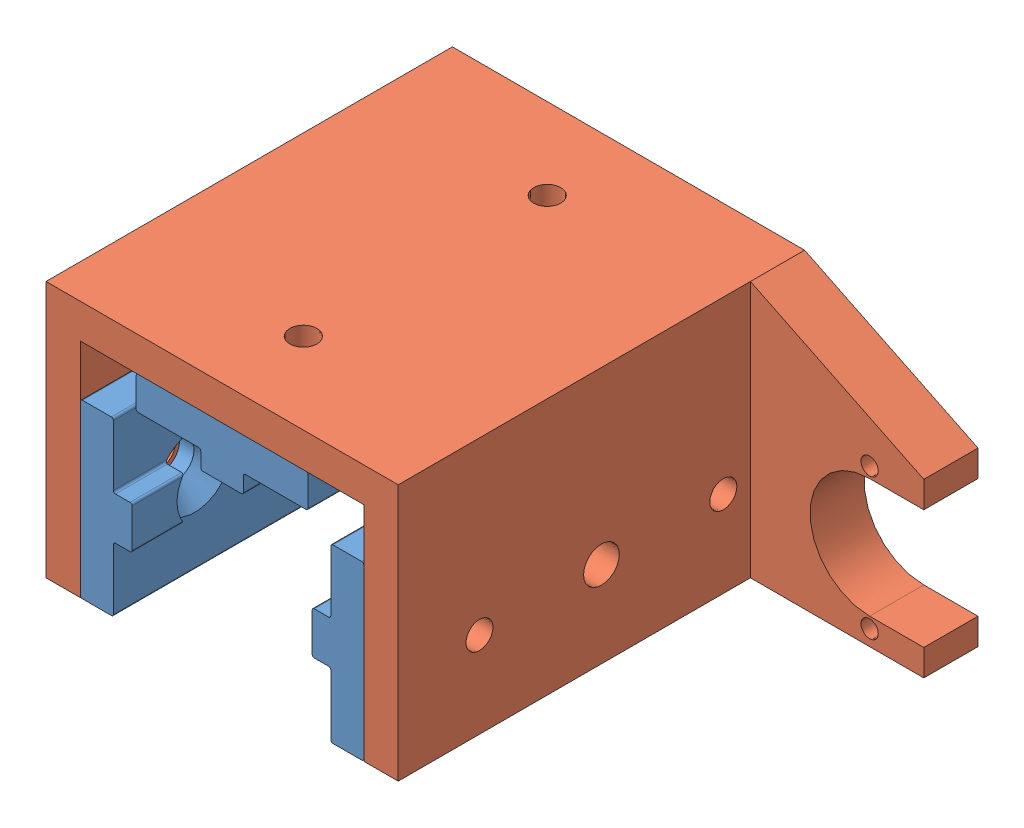
SolidWorks assembly Frame Carriage Assembly RH, configuration Default. Lengths in mm.
Overall size (97 47.37 75).
4 component instances, 2 part files, 19 mates.
Components (placement in the parent):
- Frame Carriage Bearing-1: Frame Carriage Bearing [Default] at (-8.5993 49.5816 28.728) size (9.53 31.75 75)
- Frame Carriage Bearing-2: Frame Carriage Bearing [Default] at (31.5087 49.5816 28.728) x (-1 0 0) z (0 0 1) size (9.53 31.75 75)
- Frame Carriage Bearing-3: Frame Carriage Bearing [Default] at (11.4547 68.6316 78.328) x (0 -1 0) z (0 0 -1) size (9.53 31.75 75)
- Frame Carriage Body RH-1: Frame Carriage Body RH [Default] at (-21.0453 33.7076 -58.972) size (97 47.37 75)
Mates (geometry in assembly coordinates):
- Coincident1: coincident: plane of ? through (-13.8584 24.4943 92.1884) normal (0 0 1); plane of Frame Carriage Bearing-1 through (-7.1274 55.8623 92.1884) normal (0 0 1)
- Coincident2: coincident: plane of ? through (-13.8584 24.4943 92.1884) normal (0 0 1); plane of Frame Carriage Bearing-3 through (34.1356 65.1333 92.1884) normal (0 0 1)
- Coincident3: coincident: plane of ? through (-13.8584 24.4943 92.1884) normal (0 0 1); plane of Frame Carriage Bearing-2 through (44.4106 24.8743 92.1884) normal (0 0 1)
- Coincident4: coincident: plane of ? through (-7.5084 24.4943 92.1884) normal (1 0 0); plane of Frame Carriage Bearing-1 through (-7.5084 55.8623 42.5884) normal (-1 0 0)
- Coincident5: coincident: plane of ? through (44.7916 65.5143 92.1884) normal (-1 0 0); plane of Frame Carriage Bearing-2 through (44.7916 24.8743 42.5884) normal (1 0 0)
- Coincident6: coincident: plane of ? through (-7.5084 65.5143 92.1884) normal (0 -1 0); plane of Frame Carriage Bearing-3 through (3.1476 65.5143 66.7884) normal (0 1 0)
- Distance2: distance = 19.05 mm: moEndPointRef_w of Frame Carriage Bearing-1; line of Frame Carriage Bearing-3 through (7.1367 68.6316 91.028) axis (-1 0 0)
- Coincident10: coincident: plane of Frame Carriage Bearing-1 through (-14.3143 33.7066 41.428) normal (0 -1 0); plane of Frame Carriage Bearing-2 through (31.8897 33.7066 41.428) normal (0 -1 0)
- Symmetric1: symmetric: plane of Frame Carriage Bearing-3 through (-4.4203 69.0126 65.628) normal (-1 0 0); plane of Frame Carriage Bearing-3 through (27.3297 74.3466 65.628) normal (1 0 0); plane of assembly
- Coincident11: coincident: plane of Frame Carriage Bearing-3 through (36.218 70.7626 91.1503) normal (0 0 1); plane of ? through (-11.776 30.1509 91.1503) normal (0 0 1)
- Coincident12: coincident: plane of Frame Carriage Bearing-2 through (46.874 30.5319 42.5884) normal (1 0 0); plane of ? through (46.874 71.1709 91.1503) normal (-1 0 0)
- Coincident13: coincident: plane of Frame Carriage Bearing-2 through (41.159 30.1509 42.5884) normal (0 -1 0); plane of ? through (53.224 30.1509 91.1503) normal (0 -1 0)
- Coincident14: coincident: plane of Frame Carriage Bearing-1 through (-5.426 61.5199 42.5884) normal (-1 0 0); plane of ? through (-5.426 30.1509 91.1503) normal (1 0 0)
- Coincident15: coincident: plane of Frame Carriage Bearing-1 through (-14.6953 65.0756 41.428) normal (-1 0 0); plane of Frame Carriage Body RH-1 through (-14.6953 33.7076 16.028) normal (1 0 0)
- Coincident16: coincident: plane of Frame Carriage Bearing-3 through (-4.0393 74.7276 65.628) normal (0 1 0); plane of Frame Carriage Body RH-1 through (-7.1953 74.7276 16.028) normal (0 -1 0)
- Coincident17: coincident: plane of Frame Carriage Bearing-2 through (37.6047 34.0876 41.428) normal (1 0 0); plane of Frame Carriage Body RH-1 through (37.6047 67.2276 16.028) normal (-1 0 0)
- Coincident18: coincident: plane of Frame Carriage Bearing-2 through (37.2237 34.0876 91.028) normal (0 0 1); plane of Frame Carriage Body RH-1 through (-21.0453 33.7076 91.028) normal (0 0 1)
- Coincident19: coincident: plane of Frame Carriage Bearing-3 through (26.9487 74.3466 91.028) normal (0 0 1); plane of Frame Carriage Body RH-1 through (-21.0453 33.7076 91.028) normal (0 0 1)
- Coincident20: coincident: plane of Frame Carriage Bearing-1 through (-14.3143 65.0756 91.028) normal (0 0 1); plane of Frame Carriage Body RH-1 through (-21.0453 33.7076 91.028) normal (0 0 1)
